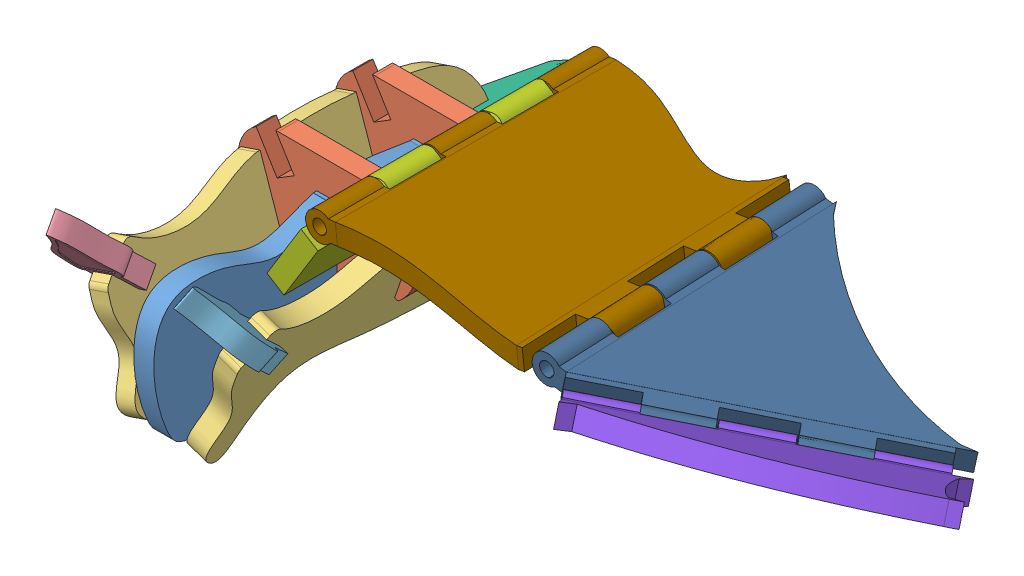
SolidWorks assembly Assem1, configuration Default. Lengths in mm.
Overall size (98.98 34.44 65.16).
13 component instances, 10 part files, 38 mates.
Components (placement in the parent):
- BODY_MIDDLE-1: BODY_MIDDLE [Default] at (-148.5512 39.3013 69.7516) size (2.5 17.11 46.47)
- BACK_JOINT-1: BACK_JOINT [Default] at (-148.5512 34.1204 122.2516) size (22.13 13.47 2.5)
- BACK_JOINT-2: BACK_JOINT [Default] at (-148.5512 34.1204 134.3016) size (22.13 13.47 2.5)
- BODY_SIDE-1: BODY_SIDE [Default] at (-158.1023 39.0719 69.7516) x (0.945519 0.325568 0) z (0 0 1) size (2.5 18.22 47.01)
- BODY_SIDE-2: BODY_SIDE [Default] at (-149.782 39.8858 69.7516) x (0.945519 -0.325568 0) z (0 0 1) size (2.5 18.22 47.01)
- EAR_LEFT-1: EAR_LEFT [Default] at (-157.3858 67.8694 63.4671) x (0.945519 0.325568 0) z (0.230211 -0.668583 0.707107) size (6.71 14.16 2.5)
- EAR_RIGHT-1: EAR_RIGHT [Default] at (-116.0858 56.834 63.4671) x (0.945519 -0.325568 0) z (-0.230211 -0.668583 0.707107) size (6.71 14.16 2.5)
- LEG-1: LEG [Default] at (-185.2446 25.3397 81.6498) x (-0.774599 -0.266716 -0.573462) z (-0.325568 0.945519 0) size (9.93 14.61 2.5)
- LEG-2: LEG [Default] at (-112.1367 48.9777 81.6498) x (0.774599 -0.266716 -0.573462) z (-0.325568 -0.945519 0) size (9.93 14.61 2.5)
- Final_Body_Hinge_Special-1: Final_Body_Hinge_Special [Default] at (-105.8409 129.0585 -7.6523) x (-0.523412 -0.85208 0) z (0 0 1) size (12.25 3.5 35)
- Inner_Wing-1: Inner_Wing [Default] at (0.5128 40.881 33.9066) x (-0.630561 -0.429569 -0.646424) z (-0.759271 0.168709 0.628526) size (16.42 3.5 37.21)
- Wing_Middle_Part-1: Wing_Middle_Part [Default] at (-232.4031 182.0015 41.8123) x (-0.993347 -0.115158 0) z (0 0 -1) size (36.73 3.5 40.25)
- Wing_Edge_New-1: Wing_Edge_New [Default] at (-68.184 89.1685 84.9543) x (0.000723 0.015978 0.999872) z (-0.204409 -0.978758 0.015788) size (35.95 34.28 3.51)
Mates (geometry in assembly coordinates):
- Coincident14: coincident anti-aligned: plane of BODY_SIDE-2 through (-148.1955 44.4933 74.6246) normal (0.230211 0.668583 0.707107); plane of EAR_RIGHT-1 through (-117.8707 51.6503 57.9847) normal (-0.230211 -0.668583 -0.707107)
- Parallel4: parallel anti-aligned: line of BODY_SIDE-2 through (-145.8976 51.1669 67.5665) axis (0.230211 0.668583 0.707107); line of EAR_RIGHT-1 through (-145.8976 51.1669 67.5665) axis (-0.230211 -0.668583 -0.707107)
- Coincident17: coincident anti-aligned: plane of BODY_SIDE-1 through (-159.6887 43.6794 74.6246) normal (-0.230211 0.668583 0.707107); plane of EAR_LEFT-1 through (-155.6009 62.6857 57.9847) normal (0.230211 -0.668583 -0.707107)
- Parallel5: parallel anti-aligned: line of BODY_SIDE-1 through (-161.9866 50.353 67.5665) axis (-0.230211 0.668583 0.707107); line of EAR_LEFT-1 through (-161.9866 50.353 67.5665) axis (0.230211 -0.668583 -0.707107)
- Coincident26: coincident anti-aligned: line of BODY_SIDE-1 through (-161.9866 50.353 67.5665) axis (-0.230211 0.668583 0.707107); line of EAR_LEFT-1 through (-161.9866 50.353 67.5665) axis (0.230211 -0.668583 -0.707107)
- Coincident27: coincident anti-aligned: line of BODY_SIDE-1 through (-160.1984 52.8384 65.7987) axis (-0.230211 0.668583 0.707107); line of EAR_LEFT-1 through (-160.1984 52.8384 65.7987) axis (0.230211 -0.668583 -0.707107)
- Coincident31: coincident anti-aligned: line of BODY_SIDE-2 through (-145.8976 51.1669 67.5665) axis (0.230211 0.668583 0.707107); line of EAR_RIGHT-1 through (-145.8976 51.1669 67.5665) axis (-0.230211 -0.668583 -0.707107)
- Coincident32: coincident anti-aligned: line of BODY_SIDE-2 through (-142.9583 52.0244 65.7987) axis (0.230211 0.668583 0.707107); line of EAR_RIGHT-1 through (-142.9583 52.0244 65.7987) axis (-0.230211 -0.668583 -0.707107)
- Coincident33: coincident aligned: line of BODY_SIDE-2 through (-144.2919 48.1514 25.6016) axis (0 0 -1); line of LEG-2 through (-144.2919 48.1514 28.1016) axis (0 0 -1)
- Coincident34: coincident anti-aligned: line of BODY_SIDE-2 through (-147.4696 46.6015 23.1016) axis (0 0 1); line of LEG-2 through (-147.4696 46.6015 29.8516) axis (0 0 -1)
- Coincident35: coincident anti-aligned: plane of BODY_SIDE-2 through (-149.782 39.8858 25.6016) normal (0 0 -1); plane of LEG-2 through (-145.1062 45.7867 25.6016) normal (0 0 1)
- Coincident36: coincident aligned: line of BODY_SIDE-1 through (-158.0509 46.6015 23.1016) axis (0 0 1); line of LEG-1 through (-158.0509 46.6015 25.6016) axis (0 0 1)
- Coincident37: coincident anti-aligned: line of BODY_SIDE-1 through (-161.2286 48.1514 25.6016) axis (0 0 -1); line of LEG-1 through (-161.2286 48.1514 25.6016) axis (0 0 1)
- Coincident38: coincident anti-aligned: plane of BODY_SIDE-1 through (-158.1023 39.0719 25.6016) normal (0 0 -1); plane of LEG-1 through (-161.2289 48.1523 25.6016) normal (0 0 1)
- Coincident56: coincident anti-aligned: line of BODY_MIDDLE-1 through (-151.5512 50.0299 46.8016) axis (0 1 0); line of BACK_JOINT-2 through (-151.5512 50.0299 46.8016) axis (0 -1 0)
- Coincident57: coincident aligned: line of BODY_MIDDLE-1 through (-154.0512 50.0299 49.3016) axis (0 1 0); line of BACK_JOINT-2 through (-154.0512 45.1531 49.3016) axis (0 1 0)
- Coincident58: coincident anti-aligned: plane of BODY_MIDDLE-1 through (-151.5512 50.0299 46.8016) normal (0 1 0); plane of BACK_JOINT-2 through (-154.2762 50.0299 49.3016) normal (0 -1 0)
- Coincident59: coincident anti-aligned: line of BODY_MIDDLE-1 through (-151.5512 50.0299 34.7516) axis (0 1 0); line of BACK_JOINT-1 through (-151.5512 50.0299 34.7516) axis (0 -1 0)
- Coincident60: coincident aligned: line of BODY_MIDDLE-1 through (-154.0512 50.0299 37.2516) axis (0 1 0); line of BACK_JOINT-1 through (-154.0512 45.1531 37.2516) axis (0 1 0)
- Coincident61: coincident anti-aligned: plane of BODY_MIDDLE-1 through (-151.5512 50.0299 37.7016) normal (0 1 0); plane of BACK_JOINT-1 through (-154.2762 50.0299 37.2516) normal (0 -1 0)
- Coincident62: coincident anti-aligned: line of BACK_JOINT-2 through (-143.9253 49.216 49.3016) axis (-0.325568 -0.945519 0); line of BODY_SIDE-2 through (-143.9253 49.216 49.3016) axis (0.325568 0.945519 0)
- Coincident63: coincident aligned: line of BACK_JOINT-2 through (-146.2891 50.0299 46.8016) axis (-0.325568 -0.945519 0); line of BODY_SIDE-2 through (-144.3029 55.7983 46.8016) axis (-0.325568 -0.945519 0)
- Coincident64: coincident anti-aligned: line of BACK_JOINT-1 through (-143.9253 49.216 34.7516) axis (-0.325568 -0.945519 0); line of BODY_SIDE-2 through (-143.9253 49.216 34.7516) axis (0.325568 0.945519 0)
- Coincident65: coincident anti-aligned: plane of BACK_JOINT-1 through (-146.2891 50.0299 37.2516) normal (-0.325568 -0.945519 0); plane of BODY_SIDE-2 through (-146.2891 50.0299 37.7016) normal (0.325568 0.945519 0)
- Coincident66: coincident aligned: line of BACK_JOINT-2 through (-157.7806 45.8165 49.3016) axis (-0.325568 0.945519 0); line of BODY_SIDE-1 through (-159.2314 50.0299 49.3016) axis (-0.325568 0.945519 0)
- Coincident67: coincident anti-aligned: line of BACK_JOINT-2 through (-161.1311 47.8684 46.8016) axis (-0.325568 0.945519 0); line of BODY_SIDE-1 through (-163.5814 54.9844 46.8016) axis (0.325568 -0.945519 0)
- Coincident68: coincident aligned: line of BACK_JOINT-1 through (-161.1311 47.8684 34.7516) axis (-0.325568 0.945519 0); line of BODY_SIDE-1 through (-161.5952 49.216 34.7516) axis (-0.325568 0.945519 0)
- Coincident69: coincident anti-aligned: plane of BACK_JOINT-1 through (-160.626 49.5497 37.2516) normal (0.325568 -0.945519 0); plane of BODY_SIDE-1 through (-161.5952 49.216 37.7016) normal (-0.325568 0.945519 0)
- Coincident72: coincident anti-aligned: line of BACK_JOINT-2 through (-146.5979 53.5526 49.3016) axis (0.523412 0.85208 0); line of Final_Body_Hinge_Special-1 through (-146.5979 53.5526 49.3016) axis (-0.523412 -0.85208 0)
- Parallel21: parallel anti-aligned: line of BACK_JOINT-1 through (-146.4245 58.6113 34.7516) axis (-0.523412 -0.85208 0); line of Final_Body_Hinge_Special-1 through (-149.7622 53.1491 34.8016) axis (0.523412 0.85208 0)
- Parallel22: parallel aligned: line of BACK_JOINT-1 through (-143.9899 57.7983 34.7516) axis (0 0 1); line of Final_Body_Hinge_Special-1 through (-146.5979 53.5526 34.8016) axis (0 0 1)
- Coincident75: coincident anti-aligned: plane of BACK_JOINT-2 through (-146.5979 53.5526 46.8016) normal (0.523412 0.85208 0); plane of Final_Body_Hinge_Special-1 through (-149.1478 55.1189 49.8016) normal (-0.523412 -0.85208 0)
- Concentric1: concentric aligned: circle of Final_Body_Hinge_Special-1; circle of Wing_Middle_Part-1
- Coincident78: coincident anti-aligned: plane of Final_Body_Hinge_Special-1 through (-144.2663 62.0959 31.8016) normal (0 0 -1); plane of Wing_Middle_Part-1 through (-141.2678 59.9088 31.8016) normal (0 0 1)
- Coincident79: coincident anti-aligned: plane of Wing_Middle_Part-1 through (-110.0364 64.0403 57.8856) normal (0.049605 0.005751 0.998752); plane of Wing_Edge_New-1 through (-108.1109 66.6287 57.7751) normal (-0.049605 -0.005751 -0.998752)
- Concentric2: concentric aligned: circle of Wing_Middle_Part-1; circle of Wing_Edge_New-1
- Coincident80: coincident anti-aligned: plane of Inner_Wing-1 through (-99.48 65.5846 63.4738) normal (0.759271 -0.168709 -0.628526); plane of Wing_Edge_New-1 through (-100.5558 62.0643 63.1191) normal (-0.759271 0.168709 0.628526)
- Concentric3: concentric anti-aligned: circle of Inner_Wing-1; circle of Wing_Edge_New-1
